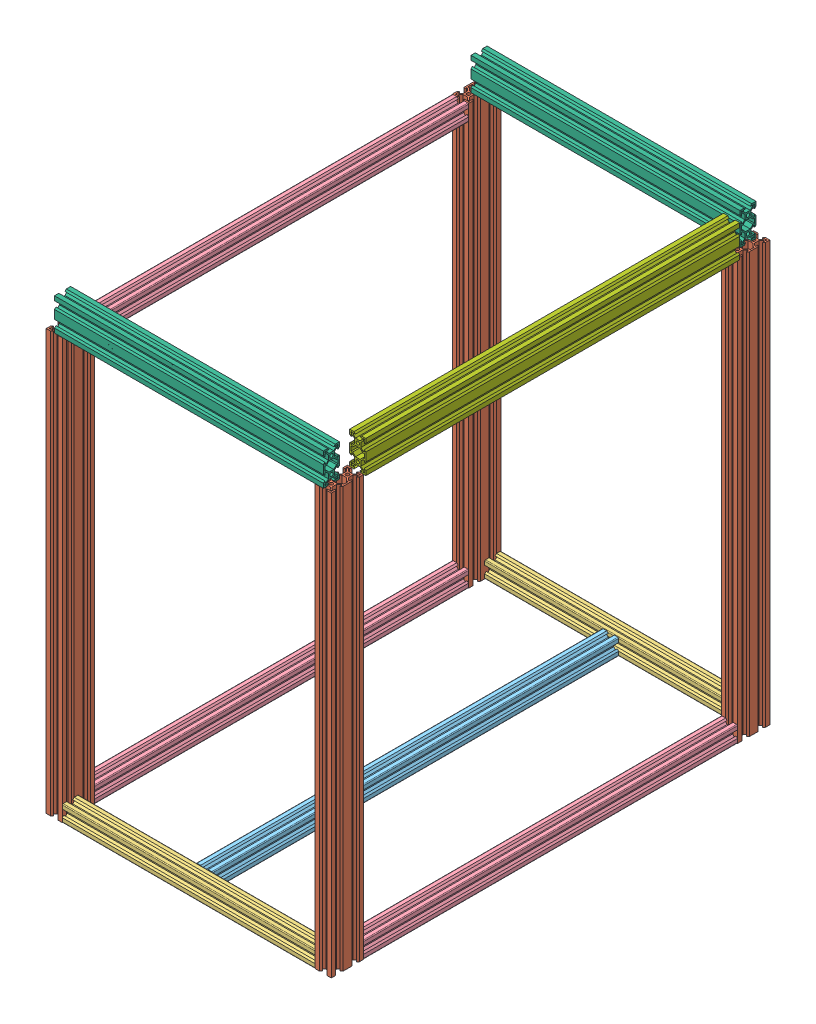
SolidWorks assembly Assem1, configuration Default. Lengths in mm.
Overall size (375.74 561 563.02).
14 component instances, 7 part files, 34 mates.
Components (placement in the parent):
- TestMaix AssemPlate-1: TestMaix AssemPlate [Default] at (2.1228 8.403 23.285) size (20 1 20)
- Maix VProfil 20x40 ABCD 520mm-1: Maix VProfil 20x40 ABCD 520mm [Default] at (375.1228 529.403 63.233) x (0 0 -1) z (0 1 0) size (40 20 520)
- Maix VProfil 20x20 HJ 313mm-1: Maix VProfil 20x20 HJ 313mm [Default] at (355.1228 9.403 43.2331) x (0 0 -1) z (1 0 0) size (20 20 313)
- Maix VProfil 20x40 ABCD 520mm-3: Maix VProfil 20x40 ABCD 520mm [Default] at (42.1228 529.403 63.2369) x (0 0 -1) z (0 1 0) size (40 20 520)
- Maix VProfil 20x20 LMN 463mm-1: Maix VProfil 20x20 LMN 463mm [Default] at (42.1228 9.403 63.2369) x (-1 0 0) z (0 0 -1) size (20 20 463)
- Maix VProfil 20x20 LMN 463mm-2: Maix VProfil 20x20 LMN 463mm [Default] at (42.1228 509.403 63.2369) x (-1 0 0) z (0 0 -1) size (20 20 463)
- Maix VProfil 20x20 LMN 463mm-3: Maix VProfil 20x20 LMN 463mm [Default] at (375.1228 9.403 63.233) x (-1 0 0) z (0 0 -1) size (20 20 463)
- Maix VProfil 20x40 ABCD 520mm-4: Maix VProfil 20x40 ABCD 520mm [Default] at (42.115 529.403 566.2407) x (0.000194 0 -1) z (0 1 0) size (40 20 520)
- Maix VProfil 20x40 ABCD 520mm-5: Maix VProfil 20x40 ABCD 520mm [Default] at (375.115 529.403 566.2368) x (0.000194 0 -1) z (0 1 0) size (40 20 520)
- Maix VProfil 20x20 HJ 313mm-2: Maix VProfil 20x20 HJ 313mm [Default] at (355.115 9.403 566.3015) x (0.000194 0 -1) z (1 0 0.000194) size (20 20 313)
- Maix VProfil 20x20 K 503mm-1: Maix VProfil 20x20 K 503mm [Default] at (207.9813 9.403 43.2331) x (-1 0 0) z (0 0 -1) size (20 20 503)
- Maix VProfil 20x40 EF 333mm-1: Maix VProfil 20x40 EF 333mm [Default] at (365.1228 569.4069 50.2712) x (0 -1 0.000194) z (1 0 0) size (40 20 333)
- Maix VProfil 20x40 G 463mm-1: Maix VProfil 20x40 G 463mm [Default] at (377.8549 569.4069 63.233) x (0.000194 -1 0) z (0 0 -1) size (40 20 463)
- Maix VProfil 20x40 EF 333mm-3: Maix VProfil 20x40 EF 333mm [Default] at (365.1151 569.4069 566.0257) x (0 -1 0.000194) z (1 0 0.000194) size (40 20 333)
Mates (geometry in assembly coordinates):
- Coincident7: coincident anti-aligned: plane of Maix VProfil 20x40 ABCD 520mm-1 through (355.1228 9.403 23.2331) normal (-1 0 0); plane of Maix VProfil 20x20 HJ 313mm-1 through (355.1228 28.403 24.2331) normal (1 0 0)
- Coincident8: coincident aligned: plane of Maix VProfil 20x40 ABCD 520mm-1 through (375.1228 9.403 63.233) normal (0 -1 0); plane of Maix VProfil 20x20 HJ 313mm-1 through (42.1228 9.403 24.2331) normal (0 -1 0)
- Coincident10: coincident aligned: line of Maix VProfil 20x40 ABCD 520mm-1 through (355.1228 9.403 23.2331) axis (0 1 0); line of Maix VProfil 20x20 HJ 313mm-1 through (355.1228 24.0776 23.2331) axis (0 1 0)
- Coincident13: coincident anti-aligned: plane of Maix VProfil 20x20 HJ 313mm-1 through (42.1228 28.403 24.2331) normal (-1 0 0); plane of Maix VProfil 20x40 ABCD 520mm-3 through (42.1228 9.403 28.5969) normal (1 0 0)
- Coincident14: coincident aligned: plane of Maix VProfil 20x20 HJ 313mm-1 through (42.1228 9.403 24.2331) normal (0 -1 0); plane of Maix VProfil 20x40 ABCD 520mm-3 through (42.1228 9.403 63.2369) normal (0 -1 0)
- Coincident15: coincident aligned: line of Maix VProfil 20x20 HJ 313mm-1 through (42.1228 24.0776 23.2331) axis (0 1 0); line of Maix VProfil 20x40 ABCD 520mm-3 through (42.1228 9.403 23.2331) axis (0 1 0)
- Coincident16: coincident anti-aligned: plane of Maix VProfil 20x40 ABCD 520mm-3 through (27.4828 9.403 63.2369) normal (0 0 1); plane of Maix VProfil 20x20 LMN 463mm-1 through (23.1228 28.403 63.2369) normal (0 0 -1)
- Coincident17: coincident aligned: plane of Maix VProfil 20x40 ABCD 520mm-3 through (42.1228 9.403 63.2369) normal (0 -1 0); plane of Maix VProfil 20x20 LMN 463mm-1 through (23.1228 9.403 526.2369) normal (0 -1 0)
- Coincident18: coincident aligned: line of Maix VProfil 20x40 ABCD 520mm-3 through (22.1228 9.403 63.2369) axis (0 1 0); line of Maix VProfil 20x20 LMN 463mm-1 through (22.1228 10.403 63.2369) axis (0 1 0)
- Coincident19: coincident aligned: plane of Maix VProfil 20x40 ABCD 520mm-3 through (42.1228 529.403 63.2369) normal (0 1 0); plane of Maix VProfil 20x20 LMN 463mm-2 through (27.4828 529.403 526.2369) normal (0 1 0)
- Coincident20: coincident anti-aligned: plane of Maix VProfil 20x40 ABCD 520mm-3 through (27.4828 9.403 63.2369) normal (0 0 1); plane of Maix VProfil 20x20 LMN 463mm-2 through (23.1228 528.403 63.2369) normal (0 0 -1)
- Coincident21: coincident aligned: line of Maix VProfil 20x40 ABCD 520mm-3 through (22.1228 9.403 63.2369) axis (0 1 0); line of Maix VProfil 20x20 LMN 463mm-2 through (22.1228 510.403 63.2369) axis (0 1 0)
- Coincident22: coincident anti-aligned: plane of Maix VProfil 20x40 ABCD 520mm-1 through (360.4828 9.403 63.233) normal (0 0 1); plane of Maix VProfil 20x20 LMN 463mm-3 through (356.1228 28.403 63.233) normal (0 0 -1)
- Coincident23: coincident aligned: plane of Maix VProfil 20x40 ABCD 520mm-1 through (375.1228 9.403 63.233) normal (0 -1 0); plane of Maix VProfil 20x20 LMN 463mm-3 through (356.1228 9.403 526.233) normal (0 -1 0)
- Coincident24: coincident anti-aligned: line of Maix VProfil 20x40 ABCD 520mm-1 through (375.1228 9.403 63.233) axis (0 1 0); line of Maix VProfil 20x20 LMN 463mm-3 through (375.1228 14.763 63.233) axis (0 -1 0)
- Coincident25: coincident aligned: plane of Maix VProfil 20x40 ABCD 520mm-1 through (375.1228 9.403 63.233) normal (0 -1 0); plane of Maix VProfil 20x40 ABCD 520mm-5 through (375.115 9.403 566.2368) normal (0 -1 0)
- Coincident26: coincident aligned: plane of Maix VProfil 20x40 ABCD 520mm-3 through (42.1228 9.403 63.2369) normal (0 -1 0); plane of Maix VProfil 20x40 ABCD 520mm-4 through (42.115 9.403 566.2407) normal (0 -1 0)
- Coincident27: coincident anti-aligned: plane of Maix VProfil 20x20 LMN 463mm-1 through (23.1228 28.403 526.2369) normal (0 0 1); plane of Maix VProfil 20x40 ABCD 520mm-4 through (42.1228 9.403 526.2369) normal (0 0 -1)
- Coincident28: coincident anti-aligned: plane of Maix VProfil 20x20 LMN 463mm-3 through (356.1228 28.403 526.233) normal (0 0 1); plane of Maix VProfil 20x40 ABCD 520mm-5 through (375.1228 9.403 526.233) normal (0 0 -1)
- Coincident29: coincident aligned: line of Maix VProfil 20x20 LMN 463mm-1 through (22.1228 10.403 526.2369) axis (0 1 0); line of Maix VProfil 20x40 ABCD 520mm-4 through (22.1228 9.403 526.2369) axis (0 1 0)
- Coincident30: coincident aligned: line of Maix VProfil 20x20 LMN 463mm-3 through (355.1228 10.403 526.233) axis (0 1 0); line of Maix VProfil 20x40 ABCD 520mm-5 through (355.1228 9.403 526.233) axis (0 1 0)
- Coincident31: coincident anti-aligned: plane of Maix VProfil 20x40 ABCD 520mm-4 through (42.1189 9.403 546.2407) normal (1 0 0.000194); plane of Maix VProfil 20x20 HJ 313mm-2 through (42.1187 28.403 547.2407) normal (-1 0 -0.000194)
- Coincident32: coincident aligned: plane of Maix VProfil 20x40 ABCD 520mm-4 through (42.115 9.403 566.2407) normal (0 -1 0); plane of Maix VProfil 20x20 HJ 313mm-2 through (42.1187 9.403 547.2407) normal (0 -1 0)
- Coincident35: coincident anti-aligned: line of Maix VProfil 20x40 ABCD 520mm-4 through (42.115 9.403 566.2407) axis (0 1 0); line of Maix VProfil 20x20 HJ 313mm-2 through (42.115 14.763 566.2407) axis (0 -1 0)
- Coincident39: coincident anti-aligned: plane of Maix VProfil 20x20 HJ 313mm-1 through (42.1228 24.043 43.2331) normal (0 0 1); plane of Maix VProfil 20x20 K 503mm-1 through (188.9813 28.403 43.2331) normal (0 0 -1)
- Coincident40: coincident aligned: plane of Maix VProfil 20x20 LMN 463mm-1 through (23.1228 9.403 526.2369) normal (0 -1 0); plane of Maix VProfil 20x20 K 503mm-1 through (202.6213 9.403 546.2331) normal (0 -1 0)
- Coincident76: coincident anti-aligned: plane of Maix VProfil 20x40 ABCD 520mm-1 through (375.1228 529.403 63.233) normal (0 1 0); plane of Maix VProfil 20x40 EF 333mm-1 through (32.1228 529.403 35.6363) normal (0 -1 0)
- Coincident78: coincident anti-aligned: plane of Maix VProfil 20x40 ABCD 520mm-5 through (375.115 529.403 566.2368) normal (0 1 0); plane of Maix VProfil 20x40 G 463mm-1 through (363.22 529.403 526.233) normal (0 -1 0)
- Coincident84: coincident anti-aligned: plane of Maix VProfil 20x40 ABCD 520mm-1 through (360.4828 9.403 63.233) normal (0 0 1); plane of Maix VProfil 20x40 G 463mm-1 through (377.8549 569.4069 63.233) normal (0 0 -1)
- Distance13: distance = 10 mm anti-aligned: plane of Maix VProfil 20x40 EF 333mm-1 through (365.1228 569.4069 50.2712) normal (1 0 0); plane of Maix VProfil 20x40 ABCD 520mm-1 through (355.1228 9.403 23.2331) normal (-1 0 0)
- Coincident92: coincident anti-aligned: plane of TestMaix AssemPlate-1 through (2.1228 9.403 23.285) normal (0 1 0); plane of Maix VProfil 20x20 HJ 313mm-2 through (42.1187 9.403 547.2407) normal (0 -1 0)
- Coincident93: coincident anti-aligned: plane of TestMaix AssemPlate-1 through (22.1228 9.403 23.285) normal (1 0 0); plane of Maix VProfil 20x40 ABCD 520mm-3 through (22.1228 9.403 48.5969) normal (-1 0 0)
- Coincident103: coincident anti-aligned: plane of Maix VProfil 20x40 ABCD 520mm-4 through (42.115 529.403 566.2407) normal (0 1 0); plane of Maix VProfil 20x40 EF 333mm-3 through (32.1151 529.403 565.9688) normal (0 -1 0)
- Distance20: distance = 10 mm aligned: plane of Maix VProfil 20x40 EF 333mm-3 through (32.1151 569.4069 565.9611) normal (-1 0 -0.000194); plane of Maix VProfil 20x40 ABCD 520mm-4 through (22.1179 9.403 551.5968) normal (-1 0 -0.000194)
